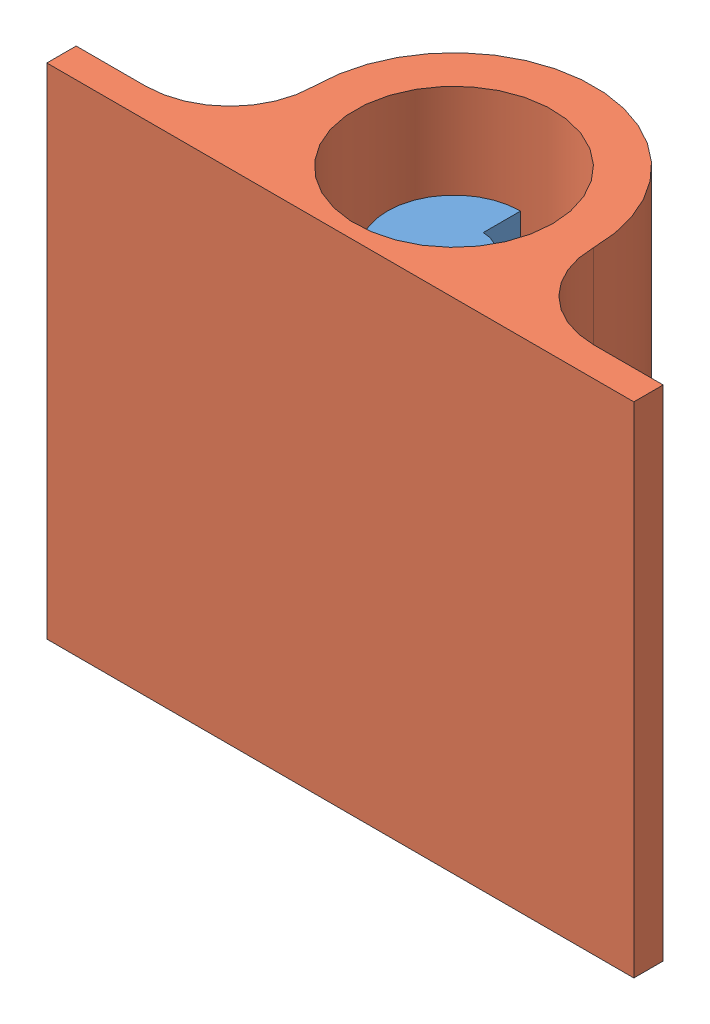
SolidWorks assembly Vibration motor enclosure, configuration Default. Lengths in mm.
Overall size (25.4 21.59 10.96).
2 component instances, 2 part files, 4 mates.
Components (placement in the parent):
- Vibration motor-1: Vibration motor [Default] at (5.37 -2.0477 15.424) size (6 17.22 6)
- Vibration Motor Enclosure-1: Vibration Motor Enclosure [Default] at (5.37 -2.0477 15.424) x (1 0 0) z (0 1 0) size (25.4 10.96 21.59)
Mates (geometry in assembly coordinates):
- InPlace1: in place: plane of Vibration motor-1 through (5.37 -2.0477 15.424) normal (0 1 0); plane of Vibration Motor Enclosure-1 through (5.37 -2.0477 15.424) normal (0 1 0); moOrthogonalPlaneRef_w of Vibration motor-1 through (5.37 -2.0477 15.424) normal (0 1 0); plane of Vibration Motor Enclosure-1 through (5.37 -2.0477 15.424) normal (0 0 -1); plane of Vibration motor-1 through (5.37 -2.0477 15.424) normal (0 1 0); unknown of Vibration Motor Enclosure-1; plane of Vibration motor-1 through (5.37 -2.0477 15.424) normal (0 1 0); unknown of Vibration Motor Enclosure-1
- Coincident1: coincident aligned: plane of Vibration motor-1; plane of Vibration Motor Enclosure-1
- Coincident2: coincident aligned: moOrthogonalPlaneRef_w of Vibration motor-1; plane of Vibration Motor Enclosure-1 through (5.37 -2.0477 15.424) normal (0 0 -1)
- Coincident3: coincident anti-aligned: moOrthogonalPlaneRef_w of Vibration motor-1; plane of Vibration Motor Enclosure-1
